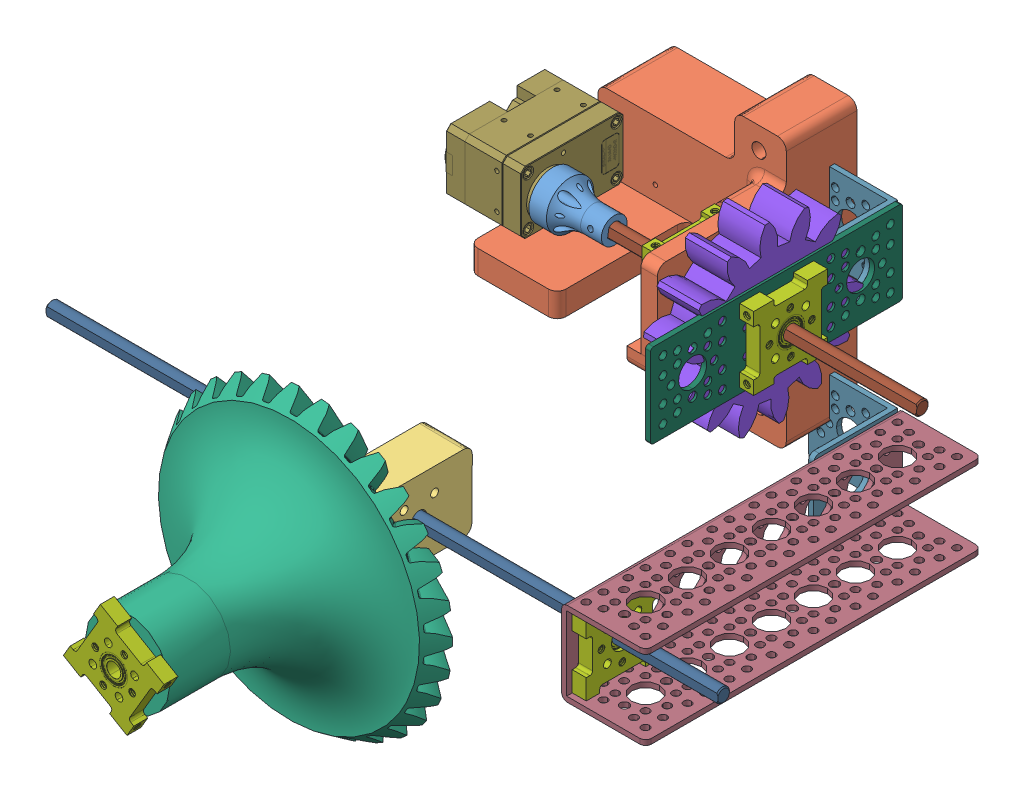
SolidWorks assembly ARMUS-REV2-000, configuration Défaut. Lengths in mm.
Overall size (318.72 216.56 271.76).
37 component instances, 22 part files, 58 mates.
Components (placement in the parent):
- ARMUS-REV2-002-1: ARMUS-REV2-002 [Default] at (115.6181 1031.7549 127.29) x (0 -0.988069 0.154009) z (0 0.154009 0.988069) size (22.05 28 22.05)
- ARMUS-REV2-004-1: ARMUS-REV2-004 [Défaut] at (117.9281 970.4739 75.3062) x (1 0 0) z (0 -1 0) size (85.41 90.57 122.11)
- ARMUS-REV2-005-1: ARMUS-REV2-005 [Défaut] at (157.9281 806.9641 75.3062) x (1 0 0) z (0 -1 0) size (85.41 90.57 122.11) (hidden)
- ARMUS-REV2-200-1: ARMUS-REV2-200 [Défaut] at (121.1548 967.4995 203.165) x (0 0 1) z (0.999969 -0.007812 0) size (54 35 20)
  - ARMUS-REV2-201-1: ARMUS-REV2-201 [Défaut] at origin size (54 35 20)
  - HUB-0_25-1: HUB-0_25 [Défaut] at (-30.0172 37.5992 -6.2696) x (-1 0 0) z (0 -1 0) size (25.4 12.7 25.4)
  - hex nut_ai-2: hex nut_ai [HNUT 0.2500-20-D-N] at (19.3798 17.5 0) x (0 0.5 0.866025) z (-1 0 0) size (11.11 12.83 5.74)
- ARMUS-REV2-300-1: ARMUS-REV2-300 [Default] at (197.2182 950 203.49) x (1 0 0) z (0 0.35014 -0.936697) size (57.21 161.95 162.56)
  - ARMUS-REV2-301-1: ARMUS-REV2-301 [Default] at origin size (50.86 161.95 162.56) (hidden)
  - Bore Side Tapped Pillow Block 1.25-1: Bore Side Tapped Pillow Block 1.25 [Default] at (-39.4159 7.6184 -28.3917) x (0 -1 0) z (0 0 1) size (33.54 6.35 33.02) (hidden)
  - Bore Side Tapped Pillow Block 1.25-2: Bore Side Tapped Pillow Block 1.25 [Default] at (4.8346 7.6184 -28.3917) x (0 -1 0) z (0 0 1) size (33.54 6.35 33.02) (hidden)
- ARMUS-REV2-400-1: ARMUS-REV2-400 [Défaut] at (121.0181 950 252.232) x (0 0 -1) z (-0.508464 -0.861083 0) size (99.55 130.43 130.79)
  - ARMUS-REV2-401-1: ARMUS-REV2-401 [Default] at origin size (93.2 130.43 130.79)
  - Bore Side Tapped Pillow Block 1.25-1: Bore Side Tapped Pillow Block 1.25 [Default] at (-58.9626 7.6184 28.3917) x (0 -1 0) z (0 0 -1) size (33.54 6.35 33.02)
  - Bore Side Tapped Pillow Block 1.25-2: Bore Side Tapped Pillow Block 1.25 [Default] at (26.0822 -28.3917 7.6184) x (0 0 -1) z (0 1 0) size (33.54 6.35 33.02)
- ARMUS-REV2-500-1: ARMUS-REV2-500 [Défaut] at (216.2682 1031.7548 127.289) x (-1 0 0) z (0 -0.682686 0.730712) size (28.58 79.69 81.28)
  - ARMUS-REV2-501-1: ARMUS-REV2-501 [Défaut] at origin size (19.05 79.69 81.28) (hidden)
  - bore_set_screw_D_hub-1: bore_set_screw_D_hub [Défaut] at (-20.7023 -52.5937 -16.7801) x (0 -1 0.000796) z (0 0.000796 1) size (20.57 9.61 20.57) (hidden)
- z_env_0-1: z_env_0 [Default] at origin size (200 1000 50) (hidden)
- hex bolt_ai-4: hex bolt_ai [HBOLT 0.2500-20x4.5x0.75-N] at (121.0181 950 336.7402) x (0 0 -1) z (0.923728 0.383049 0) size (119.08 12.85 11.13) (hidden)
- spur gear_ai-18: spur gear_ai [Inch - Spur gear 5DP 14T 20PA 0.75FW ---S14N3.0H2.0L0.5N] at (197.2182 1031.7549 127.29) x (1 0 0) z (0 0.145675 0.989332) size (19.05 79.69 81.28)
- ARMUS-REV2-100-1: ARMUS-REV2-100 [Défaut] at (197.2182 950 203.49) x (1 0 0) z (0 -0.986274 0.165118) size (50.86 161.95 162.56)
  - straight bevel pinion_ai-4: straight bevel pinion_ai [Inch - Straight bevel pinion 6DP20PT 30GT 20PA 0.75FW ---20O4H3MD0.5N] at (-9.9279 0 0) x (-1 0 0) z (0 0 -1) size (31.81 92.88 92.88) (hidden)
  - spur gear_ai-3: spur gear_ai [Inch - Spur gear 5DP 30T 20PA .75FW ---S30N3.0H2.0L0.5N] at origin size (19.05 161.95 162.56) (hidden)
- straight bevel gear_ai-7: straight bevel gear_ai [Inch - Straight bevel gear 6DP 30GT 20PT 20PA 0.75FW ---30O1.5H5.05MD0.5N] at (121.0181 950 252.232) x (0 0 -1) z (0.993195 -0.116459 0) size (99.55 130.43 130.79) (hidden)
- bore_set_screw_D_hub-1: bore_set_screw_D_hub [Défaut] at (90.1853 933.4177 255.7446) x (0 0 1) z (0.007812 0.999969 0) size (20.57 9.61 20.57)
- D-Shaft 1.25x8-1: D-Shaft 1.25x8 [Default] at (116.9936 950 203.49) x (0 1 0) z (-1 0 0) size (6.35 5.71 304.8)
- D-Shaft 1.25x6-1: D-Shaft 1.25x6 [Default] at (207.1181 1031.7549 127.29) x (0 0.988069 -0.154009) z (-1 0 0) size (6.35 5.71 152.4)
- Bore Side Tapped Pillow Block 1.25-1: Bore Side Tapped Pillow Block 1.25 [Default] at (237.8514 942.3816 175.0983) x (0 1 0) z (0 0 1) size (33.54 6.35 33.02)
- Bore Side Tapped Pillow Block 1.25-3: Bore Side Tapped Pillow Block 1.25 [Default] at (203.0706 1060.1466 134.9084) x (0 0 -1) z (0 -1 0) size (33.54 6.35 33.02)
- XM430-W350-R-1: XM430-W350-R [Default] at (96.2099 1032.2416 115.9655) x (0 1 0) z (1 0 0) size (28.5 46.5 41)
- Bore Side Tapped Pillow Block 1.25-6: Bore Side Tapped Pillow Block 1.25 [Default] at (193.2335 1024.1364 98.8983) x (0 1 0) z (0 0 1) size (33.54 6.35 33.02)
- Bore Side Tapped Pillow Block 1.25-7: Bore Side Tapped Pillow Block 1.25 [Default] at (48.8027 875.8636 98.8983) x (0 -1 0) z (0 0 1) size (33.54 6.35 33.02) (hidden)
- ARMUS-REV2-012-1: ARMUS-REV2-012 [Default] at (215 969.05 70.14) x (0 -1 0) z (0 0 1) size (38.1 38.1 152.4)
- ARMUS-REV2-010-1: ARMUS-REV2-010 [Default] at (195.95 950 70.14) x (0 1 0) z (1 0 0) size (38.1 38.1 38.1)
- ARMUS-REV2-011-3: ARMUS-REV2-011 [Default] at (215 1031.7549 146.34) x (0 0 1) z (0 1 0) size (114.3 2.29 38.1)
- ARMUS-REV2-010-2: ARMUS-REV2-010 [Default] at (195.95 1031.7549 70.14) x (0 1 0) z (1 0 0) size (38.1 38.1 38.1)
Mates (geometry in assembly coordinates):
- Coincident1: coordinate: point of z_env_0-1
- Concentric6: concentric anti-aligned: cylinder of D-Shaft 1.25x8-1 through (269.3936 950 203.49) axis (-1 0 0) radius 3.175; cylinder of Bore Side Tapped Pillow Block 1.25-1 through (217.2987 950 203.49) axis (1 0 0) radius 3.175
- Concentric33: concentric anti-aligned: cylinder of XM430-W350-R-1 through (117.6181 1031.7549 127.29) axis (1 0 0) radius 4; cylinder of spur gear_ai-18 through (248.0183 1031.7549 127.29) axis (-1 0 0) radius 6.35
- Coincident38: coincident anti-aligned: plane of XM430-W350-R-1 through (115.6181 1031.7549 127.29) normal (1 0 0); plane of ARMUS-REV2-002-1 through (115.6181 1031.7549 127.29) normal (-1 0 0)
- Concentric37: concentric: cylinder of XM430-W350-R-1 through (141.0181 1031.7549 127.29) axis (1 0 0) radius 9.75; cylinder of ARMUS-REV2-002-1 through (149.0181 1031.7549 127.29) axis (-1 0 0) radius 10.75
- Concentric38: concentric anti-aligned: cylinder of ARMUS-REV2-002-1 through (115.6171 1031.7549 127.29) axis (1 0 0) radius 3.375; cylinder of D-Shaft 1.25x6-1 through (283.3181 1031.7549 127.29) axis (-1 0 0) radius 3.175
- Parallel6: parallel anti-aligned: plane of ARMUS-REV2-002-1 through (115.6171 1034.0591 129.7039) normal (0 -0.154009 -0.988069); plane of D-Shaft 1.25x6-1 through (283.3181 1030.2638 130.0931) normal (0 0.154009 0.988069)
- Distance2: distance = 12.7 mm anti-aligned: plane of D-Shaft 1.25x6-1 through (130.9181 1031.7549 127.29) normal (-1 0 0); plane of ARMUS-REV2-002-1 through (143.6181 1031.7549 127.29) normal (1 0 0)
- Concentric39: concentric: cylinder of Bore Side Tapped Pillow Block 1.25-3 through (223.6233 1031.7549 127.29) axis (-1 0 0) radius 3.175; cylinder of D-Shaft 1.25x6-1 through (283.3181 1031.7549 127.29) axis (-1 0 0) radius 3.175
- Parallel10: parallel anti-aligned: plane of D-Shaft 1.25x8-1 through (218.5936 948.095 206.03) normal (0 0 1); plane of straight bevel gear_ai-7 through (121.0181 950 240.0653) normal (0 0 -1)
- Concentric282: concentric anti-aligned: cylinder of D-Shaft 1.25x8-1 through (269.3936 950 203.49) axis (-1 0 0) radius 3.175; cylinder of ARMUS-REV2-100-1/straight bevel pinion_ai-4 through (111.0903 950 203.49) axis (1 0 0) radius 6.35
- GearMate4: gear = 25.4 : 50.8 mm: cylinder of straight bevel gear_ai-7 through (121.0181 950 331.7601) axis (0 0 -1) radius 19.05; cylinder of ARMUS-REV2-100-1/straight bevel pinion_ai-4 through (111.0903 950 203.49) axis (1 0 0) radius 6.35
- Coincident52: coincident: point of ?; point of straight bevel gear_ai-7
- Concentric283: concentric aligned: cylinder of D-Shaft 1.25x8-1 through (269.3936 950 203.49) axis (-1 0 0) radius 3.175; cylinder of ARMUS-REV2-100-1/spur gear_ai-3 through (248.0183 950 203.49) axis (-1 0 0) radius 6.35
- Width5: width aligned: plane of spur gear_ai-18 through (197.2182 1031.7549 127.29) normal (-1 0 0); plane of ARMUS-REV2-100-1/spur gear_ai-3 through (216.2682 1031.7549 127.29) normal (1 0 0); plane of spur gear_ai-18 through (197.2182 950 203.49) normal (-1 0 0); plane of ARMUS-REV2-100-1/spur gear_ai-3 through (216.2682 950 203.49) normal (1 0 0)
- Tangent4: tangent: circle of spur gear_ai-6; circle of ARMUS-REV2-100-1/spur gear_ai-2
- GearMate5: gear = 71.12 : 152.4 mm: circle of ARMUS-REV2-100-1/spur gear_ai-2; circle of spur gear_ai-6
- Coaxiale2: concentric aligned: cylinder of straight bevel gear_ai-7 through (121.0181 950 123.962) axis (0 0 1) radius 6.35; cylinder of ARMUS-REV2-200-1/ARMUS-REV2-201-1 through (121.0181 950 208.6847) axis (0 0 1) radius 3.175
- Parallèle1: parallel aligned: plane of D-Shaft 1.25x8-1 through (269.3936 948.095 206.03) normal (0 0 1); plane of straight bevel gear_ai-7 through (121.0181 950 252.232) normal (0 0 1)
- Coaxiale3: concentric aligned: cylinder of straight bevel gear_ai-7 through (121.0181 950 123.962) axis (0 0 1) radius 6.35; cylinder of hex bolt_ai-4 through (121.0181 950 336.7402) axis (0 0 1) radius 3.175
- Tangent6: tangent: circle of ARMUS-REV2-200-1/ARMUS-REV2-003-1; plane of hex bolt_ai-4 through (121.0181 950 217.665) normal (0 0 -1)
- Coaxiale4: concentric aligned: cylinder of D-Shaft 1.25x6-1 through (283.3181 1031.7549 127.29) axis (-1 0 0) radius 3.175; cylinder of ARMUS-REV2-004-1 through (219.4291 1031.7549 127.29) axis (-1 0 0) radius 4.5
- Distance3: distance = 25 mm anti-aligned: plane of ARMUS-REV2-004-1 through (163.0181 1050.5839 150.5666) normal (-1 0 0); plane of XM430-W350-R-1 through (138.0181 1046.0049 92.04) normal (1 0 0)
- Coaxiale5: concentric anti-aligned: cylinder of D-Shaft 1.25x6-1 through (283.3181 1031.7549 127.29) axis (-1 0 0) radius 3.175; cylinder of Bore Side Tapped Pillow Block 1.25-6 through (172.6808 1031.7549 127.29) axis (1 0 0) radius 3.175
- Coïncidente3: coincident anti-aligned: plane of ARMUS-REV2-004-1 through (179.0181 1012.5639 150.5666) normal (-1 0 0); plane of Bore Side Tapped Pillow Block 1.25-6 through (179.0181 1031.7549 127.29) normal (1 0 0)
- Parallèle4: parallel aligned: plane of ARMUS-REV2-004-1 through (163.0181 1050.5839 150.5666) normal (0 1 0); plane of Bore Side Tapped Pillow Block 1.25-6 through (172.6681 1048.5189 116.876) normal (0 1 0)
- Coaxiale17: concentric aligned: cylinder of ARMUS-REV2-005-1 through (55.6081 875.1599 134.2048) axis (1 0 0) radius 1.778; cylinder of Bore Side Tapped Pillow Block 1.25-7 through (69.3681 875.1599 134.2048) axis (1 0 0) radius 1.778
- Coïncidente14: coincident anti-aligned: plane of ARMUS-REV2-005-1 through (63.0181 849.0541 150.5666) normal (1 0 0); plane of Bore Side Tapped Pillow Block 1.25-7 through (63.0181 868.2451 127.29) normal (-1 0 0)
- Concentric289: concentric aligned: cylinder of ARMUS-REV2-100-1/spur gear_ai-3 through (248.0183 950 203.49) axis (-1 0 0) radius 6.35; cylinder of ARMUS-REV2-300-1/Bore Side Tapped Pillow Block 1.25-2 through (222.6055 950 203.49) axis (-1 0 0) radius 3.175
- Concentric290: concentric aligned: cylinder of ARMUS-REV2-100-1/spur gear_ai-3 through (216.2682 949.6347 131.8864) axis (-1 0 0) radius 30.48; cylinder of ARMUS-REV2-300-1/ARMUS-REV2-301-1 through (216.2682 949.6347 131.8864) axis (-1 0 0) radius 30.48
- Coincident55: coincident aligned: plane of ARMUS-REV2-100-1/spur gear_ai-3 through (216.2682 950 203.49) normal (1 0 0); plane of ARMUS-REV2-300-1/ARMUS-REV2-301-1 through (216.2682 950 203.49) normal (1 0 0)
- Concentric298: concentric aligned: cylinder of ARMUS-REV2-400-1/ARMUS-REV2-401-1 through (121.0181 950 123.962) axis (0 0 1) radius 6.35; cylinder of straight bevel gear_ai-7 through (121.0181 950 123.962) axis (0 0 1) radius 6.35
- Coincident60: coincident aligned: plane of straight bevel gear_ai-7 through (121.0181 950 240.0653) normal (0 0 -1); plane of ARMUS-REV2-400-1/ARMUS-REV2-401-1 through (121.0181 950 240.0653) normal (0 0 -1)
- Concentric299: concentric anti-aligned: cylinder of hex bolt_ai-4 through (121.0181 950 336.7402) axis (0 0 1) radius 3.175; cylinder of ARMUS-REV2-400-1/Bore Side Tapped Pillow Block 1.25-1 through (121.0181 950 331.7474) axis (0 0 -1) radius 3.175
- Concentric304: concentric anti-aligned: cylinder of ARMUS-REV2-200-1/ARMUS-REV2-201-1 through (106.0436 957.032 196.2502) axis (0.999969 -0.007812 0) radius 1.778; cylinder of bore_set_screw_D_hub-1 through (111.0724 956.9927 196.2502) axis (-0.999969 0.007812 0) radius 3.3722
- Concentric305: concentric anti-aligned: cylinder of ARMUS-REV2-200-1/ARMUS-REV2-201-1 through (106.0436 957.032 210.0797) axis (0.999969 -0.007812 0) radius 1.778; cylinder of bore_set_screw_D_hub-1 through (111.0724 956.9927 210.0797) axis (-0.999969 0.007812 0) radius 3.3722
- Coincident65: coincident anti-aligned: plane of ARMUS-REV2-200-1/ARMUS-REV2-201-1 through (110.8817 932.5787 233.165) normal (-0.999969 0.007812 0); plane of bore_set_screw_D_hub-1 through (110.9914 946.6208 199.7076) normal (0.999969 -0.007812 0)
- Coincident66: coincident aligned: plane of spur gear_ai-18 through (197.2182 1031.7549 127.29) normal (-1 0 0); plane of ARMUS-REV2-500-1/ARMUS-REV2-501-1 through (197.2182 1031.7548 127.289) normal (-1 0 0)
- Concentric306: concentric: cylinder of D-Shaft 1.25x6-1 through (283.3181 1031.7549 127.29) axis (-1 0 0) radius 3.175; cylinder of ARMUS-REV2-500-1/bore_set_screw_D_hub-1 through (216.2682 1031.7548 127.29) axis (-1 0 0) radius 3.175
- Coincident67: coincident anti-aligned: circle of spur gear_ai-18; circle of ARMUS-REV2-500-1/ARMUS-REV2-501-1
- Concentric308: concentric anti-aligned: cylinder of ARMUS-REV2-012-1 through (215 950 89.19) axis (-1 0 0) radius 6.3627; cylinder of ARMUS-REV2-010-1 through (215 950 89.19) axis (1 0 0) radius 6.3627
- Coincident71: coincident aligned: plane of ARMUS-REV2-012-1 through (215 969.05 70.14) normal (0 0 -1); plane of ARMUS-REV2-010-1 through (195.95 950 70.14) normal (0 0 -1)
- Concentric312: concentric: cylinder of ARMUS-REV2-500-1/ARMUS-REV2-501-1 through (165.4682 1031.7548 127.289) axis (1 0 0) radius 6.35; cylinder of ARMUS-REV2-011-3 through (217.286 1031.7549 127.29) axis (1 0 0) radius 6.3627
- Coincident77: coincident aligned: plane of ARMUS-REV2-012-1 through (215 969.05 70.14) normal (0 0 -1); plane of ARMUS-REV2-011-3 through (161.1185 1012.7049 70.14) normal (0 0 -1)
- Coincident78: coincident aligned: plane of ARMUS-REV2-012-1 through (215 930.95 222.54) normal (-1 0 0); plane of ARMUS-REV2-011-3 through (215 1031.7549 146.34) normal (-1 0 0)
- Coincident79: coincident anti-aligned: plane of ARMUS-REV2-011-3 through (215 1031.7549 146.34) normal (-1 0 0); plane of ARMUS-REV2-010-2 through (215 1012.7049 72.426) normal (1 0 0)
- Concentric313: concentric aligned: cylinder of ARMUS-REV2-011-3 through (217.286 1031.7549 89.19) axis (1 0 0) radius 6.3627; cylinder of ARMUS-REV2-010-2 through (215 1031.7549 89.19) axis (1 0 0) radius 6.3627
- Coincident80: coincident aligned: plane of ARMUS-REV2-010-1 through (195.95 950 70.14) normal (0 0 -1); plane of ARMUS-REV2-010-2 through (195.95 1031.7549 70.14) normal (0 0 -1)
- Coincident81: coincident anti-aligned: plane of ARMUS-REV2-012-1 through (215 930.95 222.54) normal (-1 0 0); plane of ARMUS-REV2-010-1 through (215 930.95 72.426) normal (1 0 0)
- Distance6: distance = 129.714 mm: plane of XM430-W350-R-1 through (104.0181 1046.0049 92.04) normal (-1 0 0); plane of ARMUS-REV2-010-2 through (212.714 1031.7549 70.14) normal (-1 0 0)
- Concentric316: concentric aligned: cylinder of Bore Side Tapped Pillow Block 1.25-1 through (217.286 943.0852 210.4048) axis (-1 0 0) radius 1.778; cylinder of ARMUS-REV2-012-1 through (215 943.0852 210.4048) axis (-1 0 0) radius 1.778
- Concentric317: concentric aligned: cylinder of Bore Side Tapped Pillow Block 1.25-1 through (217.286 956.9148 210.4048) axis (-1 0 0) radius 1.778; cylinder of ARMUS-REV2-012-1 through (215 956.9148 210.4048) axis (-1 0 0) radius 1.778
- Coincident84: coincident anti-aligned: plane of Bore Side Tapped Pillow Block 1.25-1 through (217.286 950 203.49) normal (-1 0 0); plane of ARMUS-REV2-012-1 through (217.286 966.764 222.54) normal (1 0 0)
- Concentric318: concentric aligned: cylinder of Bore Side Tapped Pillow Block 1.25-3 through (223.636 1038.6697 134.2048) axis (1 0 0) radius 1.778; cylinder of ARMUS-REV2-011-3 through (217.286 1038.6697 134.2048) axis (1 0 0) radius 1.778
- Concentric319: concentric aligned: cylinder of Bore Side Tapped Pillow Block 1.25-3 through (223.636 1024.8401 134.2048) axis (1 0 0) radius 1.778; cylinder of ARMUS-REV2-011-3 through (217.286 1024.8401 134.2048) axis (1 0 0) radius 1.778
- Coincident85: coincident anti-aligned: plane of Bore Side Tapped Pillow Block 1.25-3 through (217.286 1031.7549 127.29) normal (-1 0 0); plane of ARMUS-REV2-011-3 through (217.286 1031.7549 146.34) normal (1 0 0)
- Parallel12: parallel aligned: plane of ARMUS-REV2-004-1 through (121.0181 950 60) normal (0 0 -1); plane of ARMUS-REV2-010-2 through (195.95 1031.7549 70.14) normal (0 0 -1)
- Parallel13: parallel aligned: plane of ARMUS-REV2-004-1 through (121.0181 950 60) normal (0 0 -1); plane of ARMUS-REV2-005-1 through (121.0181 786.4903 60) normal (0 0 -1)
